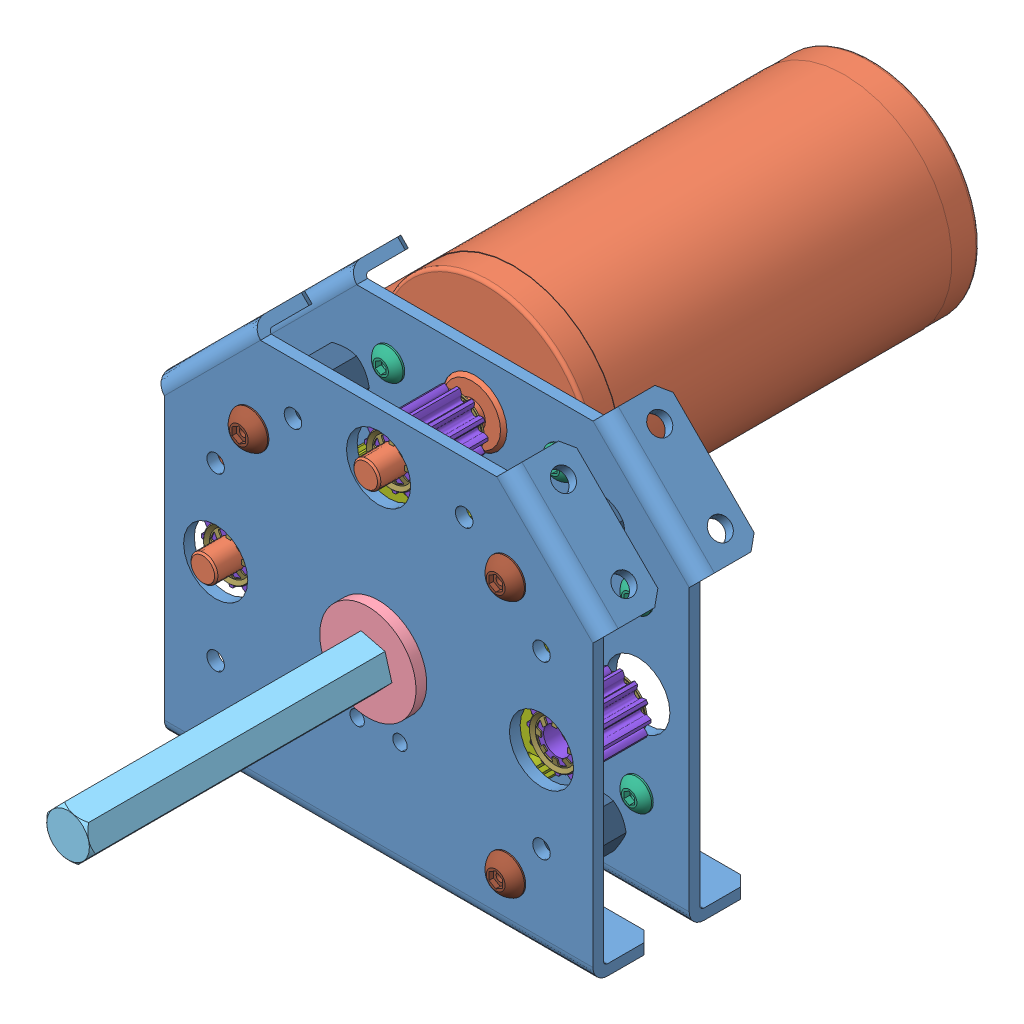
SolidWorks assembly 217-2745.20121217, configuration Default. Lengths in mm.
Overall size (147.02 132.99 243.24).
43 component instances, 15 part files, 0 mates.
Components (placement in the parent):
- 217-2745-001 Rev1_1-1: 217-2745-001 Rev1_1 [Default] at origin size (133.37 119.34 18.42)
- 217-2745-001 Rev1_1-2: 217-2745-001 Rev1_1 [Default] at (0 0 28.575) size (133.37 119.34 18.42)
- 217-2000 - CIM Motor_1-1: 217-2000 - CIM Motor_1 [Default] at (60.96 -35.56 -19.05) x (0 1 0) z (0 0 1) size (64.01 64.01 154.93)
- 217-2000 - CIM Motor_1-2: 217-2000 - CIM Motor_1 [Default] at (35.56 157.6324 -19.05) x (-1 0 0) z (0 0 1) size (64.01 64.01 154.93)
- 217-2731_1-1: 217-2731_1 [Default] at (0 0 -3.175) x (1 0 0) z (0 -1 0) size (31.12 7.94 31.12)
- 217-2734_1-1: 217-2734_1 [Default] at (0 0 34.925) x (-0.970869 0.239612 0) z (-0.239612 -0.970869 0) size (31.12 7.94 31.12)
- 217-2454-004 Rev1_1-1: 217-2454-004 Rev1_1 [Default] at (0 0 60.3758) x (0 0 1) z (-0.692944 -0.720991 0) size (140.21 12.7 16.13)
- SBS1_SBS1032-0500ZC_1-1: SBS1_SBS1032-0500ZC_1 [Default] at (-25.4 48.3362 5.7404) x (0 0 -1) z (1 0 0) size (15.78 9.29 9.24)
- 217-2715-001_64t_1-1: 217-2715-001_64t_1 [Default] at (0 0 20.6629) x (-0.239612 -0.970869 0) z (0 0 1) size (84.3 84.3 12.65)
- 217-2614-001_12t_1-1: 217-2614-001_12t_1 [Default] at (0 48.3362 17.616) x (0 1 0) z (0 0 1) size (18.29 18.29 19)
- 217-2737 Rev1_1-1: 217-2737 Rev1_1 [Default] at (0 0 11.1633) x (0.837918 -0.545796 0) z (0 0 1) size (25.39 25.4 7.82)
- 217-2617-002 Rev1_91780A359_1-1: 217-2617-002 Rev1_91780A359_1 [Default] at (38.1 -36.83 15.875) x (0.856767 0.515704 0) z (0 0 1) size (12.7 14.66 25.4)
- SBS1_SBS2520-0500SS_1-1: SBS1_SBS2520-0500SS_1 [Default] at (38.1 39.37 -3.3528) x (0 0 1) z (-0.923728 -0.383049 0) size (16.73 11.22 11.17)
- 217-2617-002 Rev1_91780A359_1-2: 217-2617-002 Rev1_91780A359_1 [Default] at (38.1 39.37 15.875) size (12.7 14.66 25.4)
- 217-2617-002 Rev1_91780A359_1-3: 217-2617-002 Rev1_91780A359_1 [Default] at (-38.1 -36.83 15.875) x (0.856767 0.515704 0) z (0 0 1) size (12.7 14.66 25.4)
- 217-2617-002 Rev1_91780A359_1-4: 217-2617-002 Rev1_91780A359_1 [Default] at (-38.1 39.37 15.875) x (0.856767 0.515704 0) z (0 0 1) size (12.7 14.66 25.4)
- SBS1_SBS2520-0500SS_1-2: SBS1_SBS2520-0500SS_1 [Default] at (38.1 39.37 35.1028) x (0 0 -1) z (1 0 0) size (16.73 11.22 11.17)
- SBS1_SBS2520-0500SS_1-3: SBS1_SBS2520-0500SS_1 [Default] at (-38.1 -36.83 35.1028) x (0 0 -1) z (1 0 0) size (16.73 11.22 11.17)
- SBS1_SBS2520-0500SS_1-4: SBS1_SBS2520-0500SS_1 [Default] at (-38.1 39.37 35.1028) x (0 0 -1) z (1 0 0) size (16.73 11.22 11.17)
- SBS1_SBS2520-0500SS_1-5: SBS1_SBS2520-0500SS_1 [Default] at (38.1 -36.83 35.1028) x (0 0 -1) z (1 0 0) size (16.73 11.22 11.17)
- SBS1_SBS2520-0500SS_1-6: SBS1_SBS2520-0500SS_1 [Default] at (38.1 -36.83 -3.3528) x (0 0 1) z (0.95771 0.287735 0) size (16.73 11.22 11.17)
- SBS1_SBS2520-0500SS_1-7: SBS1_SBS2520-0500SS_1 [Default] at (-38.1 -36.83 -3.3528) x (0 0 1) z (0.95771 0.287735 0) size (16.73 11.22 11.17)
- SBS1_SBS2520-0500SS_1-8: SBS1_SBS2520-0500SS_1 [Default] at (-38.1 39.37 -3.3528) x (0 0 1) z (0.95771 0.287735 0) size (16.73 11.22 11.17)
- 217-2614-001_12t_1-2: 217-2614-001_12t_1 [Default] at (-48.3362 0 17.616) size (18.29 18.29 19)
- 217-2614-001_12t_1-3: 217-2614-001_12t_1 [Default] at (48.3362 0 17.616) size (18.29 18.29 19)
- 217-2614-002_98430A132_1-1: 217-2614-002_98430A132_1 [Default] at (-48.3362 0 27.1156) x (0 0 1) z (-1 0 0) size (1.2 14.83 14.83)
- 217-2614-002_98430A132_1-2: 217-2614-002_98430A132_1 [Default] at (-48.3362 0 7.0496) x (0 0 1) z (-1 0 0) size (1.2 14.83 14.83)
- 217-2614-002_98430A132_1-3: 217-2614-002_98430A132_1 [Default] at (0 48.3362 27.1156) x (0 0 1) z (-1 0 0) size (1.2 14.83 14.83)
- 217-2614-002_98430A132_1-4: 217-2614-002_98430A132_1 [Default] at (0 48.3362 7.0496) x (0 0 1) z (-1 0 0) size (1.2 14.83 14.83)
- 217-2614-002_98430A132_1-5: 217-2614-002_98430A132_1 [Default] at (48.3362 0 27.1156) x (0 0 1) z (-1 0 0) size (1.2 14.83 14.83)
- 217-2614-002_98430A132_1-6: 217-2614-002_98430A132_1 [Default] at (48.3362 0 7.0496) x (0 0 1) z (-1 0 0) size (1.2 14.83 14.83)
- SBS1_SBS1032-0500ZC_1-2: SBS1_SBS1032-0500ZC_1 [Default] at (25.4 48.3362 5.7404) x (0 0 -1) z (1 0 0) size (15.78 9.29 9.24)
- SBS1_SBS1032-0500ZC_1-3: SBS1_SBS1032-0500ZC_1 [Default] at (48.3362 25.4 5.7404) x (0 0 -1) z (1 0 0) size (15.78 9.29 9.24)
- SBS1_SBS1032-0500ZC_1-4: SBS1_SBS1032-0500ZC_1 [Default] at (48.3362 -25.4 5.7404) x (0 0 -1) z (1 0 0) size (15.78 9.29 9.24)
- SBS1_SBS1032-0500ZC_1-5: SBS1_SBS1032-0500ZC_1 [Default] at (-48.3362 -25.4 5.7404) x (0 0 -1) z (1 0 0) size (15.78 9.29 9.24)
- SBS1_SBS1032-0500ZC_1-6: SBS1_SBS1032-0500ZC_1 [Default] at (-48.3362 25.4 5.7404) x (0 0 -1) z (1 0 0) size (15.78 9.29 9.24)
- 217-2745-002 Rev1_1-1: 217-2745-002 Rev1_1 [Default] at (0 0 -39.6748) size (25.4 38.1 1.57)
- 217-2428-005 Rev1_1-1: 217-2428-005 Rev1_1 [Default] at (6.35 -19.05 -19.05) x (0.995022 0.099653 0) z (-0.099653 0.995022 0) size (7.33 38.98 6.35)
- 217-2428-005 Rev1_1-2: 217-2428-005 Rev1_1 [Default] at (-6.35 -19.05 -19.05) x (0.995022 0.099653 0) z (-0.099653 0.995022 0) size (7.33 38.98 6.35)
- SBS1_SBS0832-0500SS_1-1: SBS1_SBS0832-0500SS_1 [Default] at (-6.35 -19.05 -41.8846) x (0 0 1) z (-1 0 0) size (15.36 8.02 7.99)
- SBS1_SBS0832-0500SS_1-2: SBS1_SBS0832-0500SS_1 [Default] at (6.35 -19.05 -41.8846) x (0 0 1) z (-1 0 0) size (15.36 8.02 7.99)
- SBS1_SBS0832-0500SS_1-3: SBS1_SBS0832-0500SS_1 [Default] at (6.35 -19.05 5.3848) x (0 0 -1) z (1 0 0) size (15.36 8.02 7.99)
- SBS1_SBS0832-0500SS_1-4: SBS1_SBS0832-0500SS_1 [Default] at (-6.35 -19.05 5.3848) x (0 0 -1) z (1 0 0) size (15.36 8.02 7.99)
